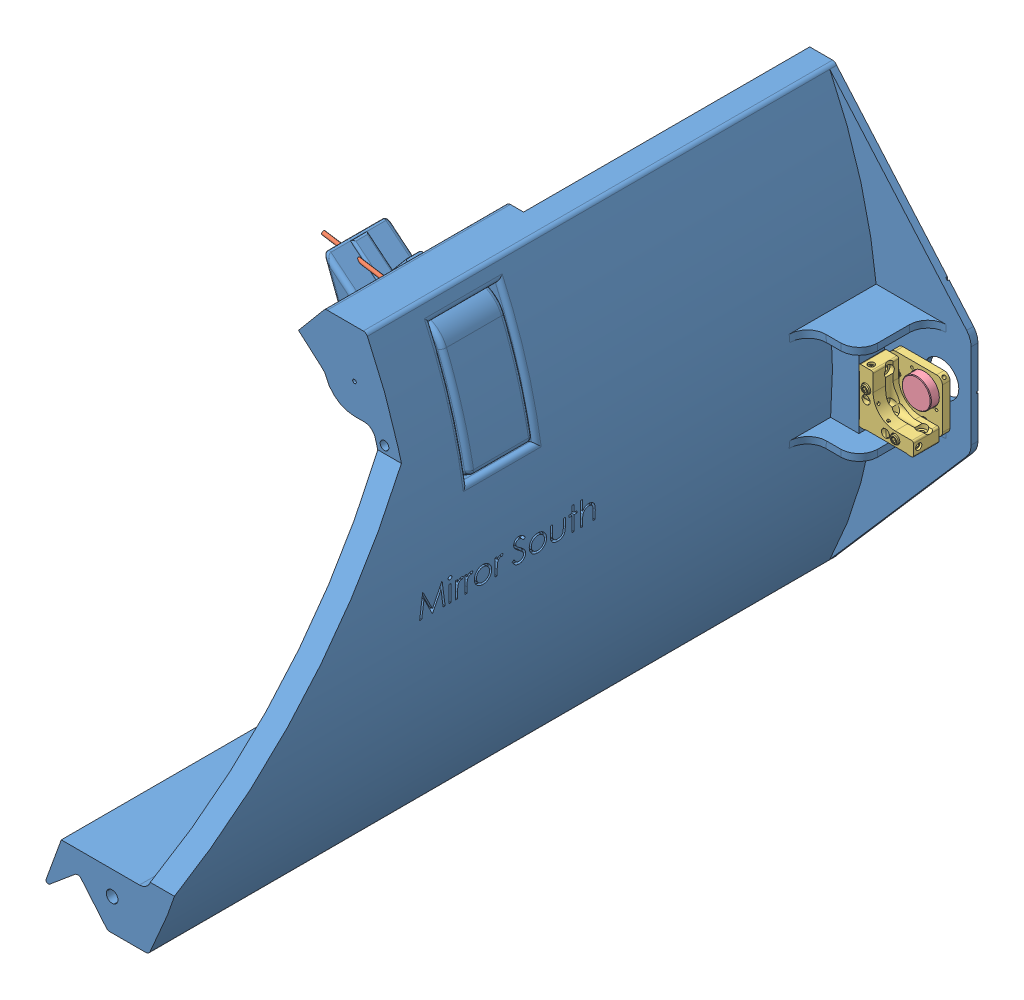
SolidWorks assembly align2_mirror_south, configuration Default. Lengths in mm.
Overall size (117.51 192.37 300).
5 component instances, 4 part files, 8 mates.
Components (placement in the parent):
- align2_mother_mirror-3: align2_mother_mirror [mirror south] at origin size (107.15 187.65 300)
- Tspring_360_LH_MC9287K143-1: Tspring_360_LH_MC9287K143 [wrap 251] at (184.7601 72.059 25.2949) x (0 0 -1) z (0.212168 -0.977233 0) size (24.67 55.31 75.8)
- align2_mother_mirror-2: align2_mother_mirror [toggle clamp] at (0.7414 -1.8569 0) x (0.999949 0.010055 0) z (0 0 1) size (63.49 57.3 28.62)
- newfocus_9762-k-1: newfocus_9762-k [Default] at (223.525 -15.875 -153) x (0 0 -1) z (0 -1 0) size (16.77 23.88 23.88)
- Mirror_Thorlabs_7710_E0W_recon-1: Mirror_Thorlabs_7710_E0W_recon [Default] at (239.4 0 -154.0373) size (12.7 12.7 6)
Mates (geometry in assembly coordinates):
- Coincident5: coincident: cylinder of align2_mother_mirror-3 through (185.0319 72.8047 -135) axis (0 0 1) radius 0.7937; line of Tspring_360_LH_MC9287K143-1 through (184.7601 72.059 107.8261) axis (0 0 -1)
- Coincident6: coincident aligned: plane of align2_mother_mirror-2 through (0.7414 -1.8569 0) normal (0 0 1); plane of assembly through (0 0 0) normal (0 0 1)
- Concentric6: concentric aligned: cylinder of align2_mother_mirror-3 through (185.0319 72.8047 -135) axis (0 0 1) radius 0.7937; cylinder of align2_mother_mirror-2 through (185.0319 72.8047 -135) axis (0 0 1) radius 0.7937
- Concentric9: concentric anti-aligned: cylinder of newfocus_9762-k-1 through (239.4 0 -157.8397) axis (0 0 1) radius 5.9563; cylinder of Mirror_Thorlabs_7710_E0W_recon-1 through (239.4 0 -151.0373) axis (0 0 -1) radius 6.35
- Coincident8: coincident anti-aligned: plane of newfocus_9762-k-1 through (239.4647 0.0635 -157.0373) normal (0 0 1); plane of Mirror_Thorlabs_7710_E0W_recon-1 through (239.4 0 -157.0373) normal (0 0 -1)
- Concentric10: concentric aligned: cylinder of align2_mother_mirror-3 through (223.525 4.445 -148.936) axis (1 0 0) radius 0.8; cylinder of newfocus_9762-k-1 through (223.5274 4.445 -148.936) axis (1 0 0) radius 1.143
- Concentric11: concentric aligned: cylinder of align2_mother_mirror-3 through (223.525 -8.255 -148.936) axis (1 0 0) radius 0.8; cylinder of newfocus_9762-k-1 through (223.6977 -8.255 -148.936) axis (1 0 0) radius 1.143
- Coincident9: coincident anti-aligned: plane of align2_mother_mirror-3 through (223.525 0 0) normal (1 0 0); plane of newfocus_9762-k-1 through (223.525 -14.4018 -147.412) normal (-1 0 0)
